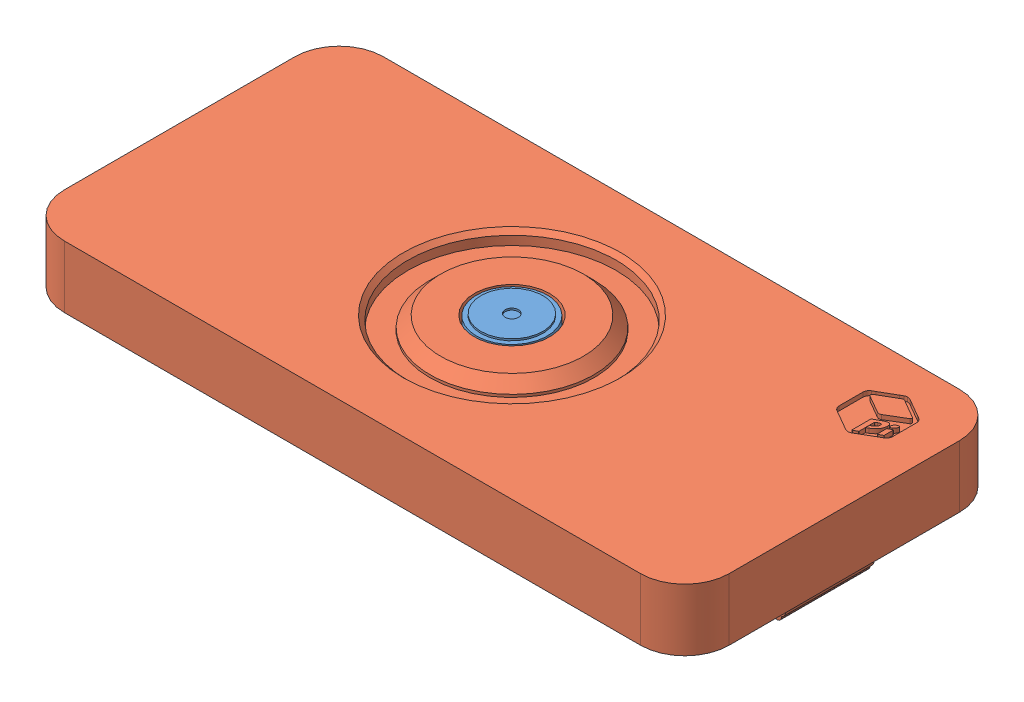
SolidWorks assembly comp_camera, configuration 默认. Lengths in mm.
Overall size (75 9.96 36).
3 component instances, 3 part files, 1 mates.
Components (placement in the parent):
- camera-1: camera [默认] at (-0.7945 -15.1911 -24.5593) x (-1 0 0) z (0 0 -1) size (28 8.7 25)
- pisugar_case_camera_cap-1: pisugar_case_camera_cap [默认] at (2.463 -9.1464 -24.5593) x (1 0 0) z (0 0 -1) size (75 9.8 36)
- focus_screw-1: focus_screw [默认] at (0.9068 -2.8595 -24.556) x (-1 0 0) z (0 0 1) size (22.76 8.1 22.76) (hidden)
Mates (geometry in assembly coordinates):
- 同心1: concentric: circle of assembly; cylinder of assembly; circle of camera-1; cylinder of pisugar_case_camera_cap-1 through (-10.7945 -16.1464 -14.0593) axis (0 1 0) radius 0.9
